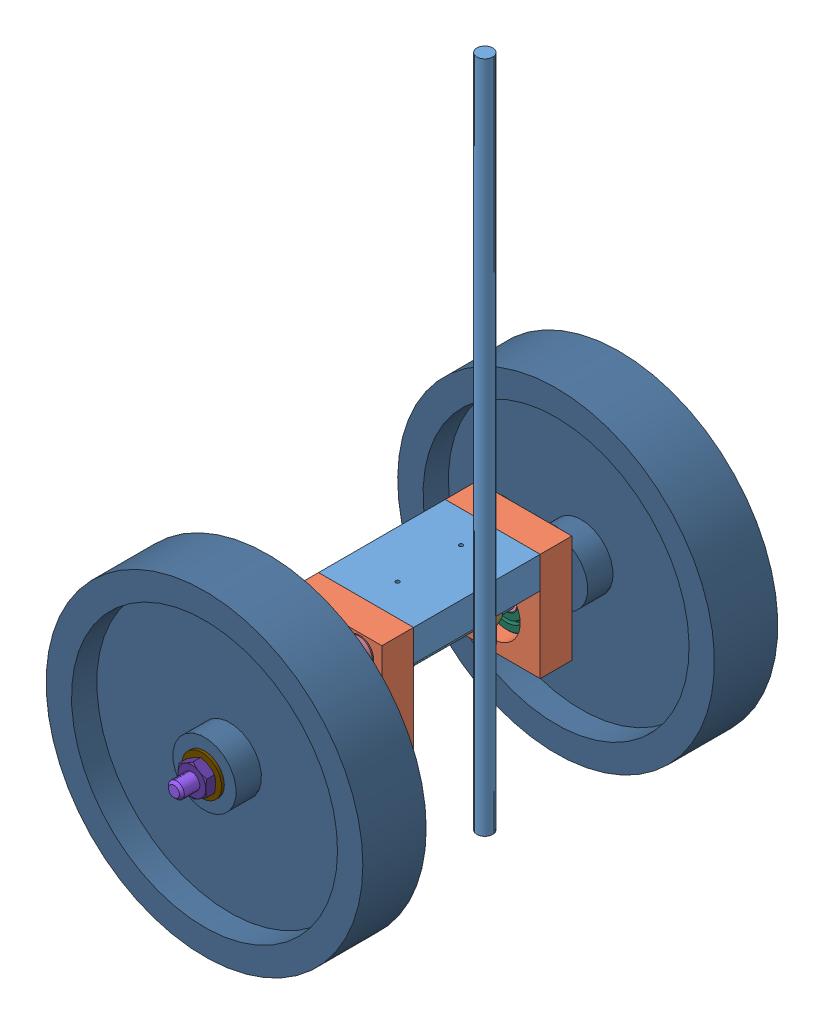
SolidWorks assembly Front Axle Assembly, configuration Default. Lengths in mm.
Overall size (164.58 298.79 190.98).
31 component instances, 20 part files, 65 mates.
Components (placement in the parent):
- Connection Front Suspention-1: Connection Front Suspention [Default] at (-53.6547 15.4423 62.2716) size (38.1 12.7 50.8)
- suspension front-1: suspension front [Default] at (-72.7047 -21.3877 74.9716) size (38.1 43.18 12.7)
- suspension front-2: suspension front [Default] at (-72.7047 -21.3877 11.4716) size (38.1 43.18 12.7)
- Slide Wing Nut-1: Slide Wing Nut [Default] at (-53.6547 8.2033 36.8716) x (0 0 1) z (0 -1 0) size (50.8 6.48 7.05)
- muffle bearing-1: muffle bearing [Default] at (-53.6547 -6.1477 -1.2284) size (8 8 7)
- muffle bearing-2: muffle bearing [Default] at (-53.6547 -6.1477 67.9716) size (8 8 7)
- Threaded Axle Front Left-1: Threaded Axle Front Left [Default] at (-53.6547 -6.1477 83.7836) x (0.967821 0.251639 0) z (0 0 1) size (6.35 6.35 135.47)
- Adapter One-Way-Bearing-1: Adapter One-Way-Bearing [Default] at (-53.6547 -6.1477 74.9716) x (-0.990269 0.139163 0) z (0 0 -1) size (45 45 20.32)
- Muffle One-Way-Bearing-1: Muffle One-Way-Bearing [Default] at (-53.6547 -6.1477 84.2916) size (15 15 11)
- Threaded Axle Front Right-1: Threaded Axle Front Right [Default] at (-53.6547 -6.1477 139.2916) x (0.848775 -0.528754 0) z (0 0 1) size (6.35 6.35 55)
- muffle wheel right-1: muffle wheel right [Default] at (-53.6547 -6.1477 95.2916) x (0.552032 0.833823 0) z (0 0 1) size (7.94 7.94 31.75)
- Wheel-1: Wheel [Default] at (-53.6547 -6.1477 114.3416) x (0.992874 0.119172 0) z (0 0 1) size (127 127 25.4)
- muffle wheel left-1: muffle wheel left [Default] at (-53.6547 -6.1477 -39.3284) size (7.94 7.94 38.1)
- Wheel-2: Wheel [Default] at (-53.6547 -6.1477 -26.6284) x (-0.36486 0.931062 0) z (0 0 1) size (127 127 25.4)
- Wingnut-1: Wingnut [Default] at (-63.224 -102.9399 -69.9379) x (0 -1 0) z (0 0 1) size (25.24 12.25 6.43)
- Button Head Hex Drive Screw 1-4-28-1: Button Head Hex Drive Screw 1-4-28 [Default] at (7.3275 5.2304 29.6861) size (11.1 11.1 16.71)
- Button Head Hex Drive Screw 1-4-28-2: Button Head Hex Drive Screw 1-4-28 [Default] at (-21.1014 44.8149 44.057) x (0.919454 0.393198 0) z (0 0 -1) size (11.1 11.1 16.71)
- Button Head Hex Drive Screw 1-4-28-3: Button Head Hex Drive Screw 1-4-28 [Default] at (-19.8729 61.5855 44.057) x (0.622111 0.782929 0) z (0 0 -1) size (11.1 11.1 16.71)
- Button Head Hex Drive Screw 1-4-28-4: Button Head Hex Drive Screw 1-4-28 [Default] at (-12.9925 5.2304 29.6861) size (11.1 11.1 16.71)
- Button Head Hex Drive Screw 1-64-1: Button Head Hex Drive Screw 1-64 [Default] at (-66.0699 34.9913 37.8914) x (-0.998887 0 -0.047164) z (0 -1 0) size (3.28 3.28 7.41)
- Button Head Hex Drive Screw 1-64-2: Button Head Hex Drive Screw 1-64 [Default] at (-37.2671 34.9913 19.4802) x (0.551582 0 -0.83412) z (0 -1 0) size (3.28 3.28 7.41)
- 608 Ball Bearing-1: 608 Ball Bearing [Default] at (-39.5024 -7.5493 -10.4793) size (22 22 7)
- 608 Ball Bearing-2: 608 Ball Bearing [Default] at (-39.5024 -7.5493 58.7207) size (22 22 7)
- One-Way-Bearing-1: One-Way-Bearing [Default] at (-39.7809 -11.9333 83.3481) x (0.996606 0.082318 0) z (0 0 1) size (35 35 11)
- Stainless Steel Thin Hex Nut 1-4-28-1: Stainless Steel Thin Hex Nut 1-4-28 [Default] at (-18.3908 36.8704 -65.2317) x (0.923728 0.383049 0) z (0.383049 -0.923728 0) size (11.11 4.67 12.83)
- Stainless Steel Thin Hex Nut 1-4-28-3: Stainless Steel Thin Hex Nut 1-4-28 [Default] at (-4.6024 -32.3769 152.9449) x (1 0 0) z (0 1 0) size (11.11 4.67 12.83)
- Stainless Steel Thin Hex Nut 1-4-28-4: Stainless Steel Thin Hex Nut 1-4-28 [Default] at (-4.6024 -32.3769 88.8139) x (1 0 0) z (0 1 0) size (11.11 4.67 12.83)
- 316 Stainless Steel Washer-1: 316 Stainless Steel Washer [Default] at (-18.7651 29.0423 -40.1203) x (1 0 0) z (0 -1 0) size (15.87 1.09 15.87)
- 316 Stainless Steel Washer-2: 316 Stainless Steel Washer [Default] at (-18.7651 -41.3376 127.8334) x (1 0 0) z (0 1 0) size (15.87 1.09 15.87)
- Wooden Rod-1: Wooden Rod [Default] at (-31.4297 -59.6477 36.8716) x (-0.156429 0 -0.987689) z (0 1 0) size (6.35 6.35 270)
- Compression Spring Break-1: Compression Spring Break [Default] at (-95.3507 -1.2922 45.8268) x (-0.627574 0.778557 0) z (0.778557 0.627574 0) size (7.88 17.75 8)
Mates (geometry in assembly coordinates):
- Coincident2: coincident: plane of Connection Front Suspention-1 through (-53.6547 15.4423 11.4716) normal (0 0 -1); plane of suspension front-2 through (-72.7047 -21.3877 11.4716) normal (0 0 1)
- Coincident3: coincident: plane of Connection Front Suspention-1 through (-72.7047 21.7923 11.4716) normal (0 1 0); plane of suspension front-2 through (-72.7047 21.7923 -1.2284) normal (0 1 0)
- Coincident4: coincident: plane of Connection Front Suspention-1 through (-72.7047 9.0923 11.4716) normal (-1 0 0); plane of suspension front-2 through (-72.7047 -21.3877 -1.2284) normal (-1 0 0)
- Coincident5: coincident: plane of Connection Front Suspention-1 through (-53.6547 15.4423 62.2716) normal (0 0 1); plane of suspension front-1 through (-72.7047 -21.3877 62.2716) normal (0 0 -1)
- Coincident6: coincident: plane of Connection Front Suspention-1 through (-72.7047 21.7923 11.4716) normal (0 1 0); plane of suspension front-1 through (-72.7047 21.7923 62.2716) normal (0 1 0)
- Coincident7: coincident: plane of Connection Front Suspention-1 through (-34.6047 9.0923 11.4716) normal (1 0 0); plane of suspension front-1 through (-34.6047 -21.3877 62.2716) normal (1 0 0)
- Coincident15: coincident: plane of Connection Front Suspention-1 through (-72.7047 9.0923 11.4716) normal (0 -1 0); plane of Slide Wing Nut-1 through (-53.6547 9.0923 36.8716) normal (0 1 0)
- Concentric7: concentric: circle of Connection Front Suspention-1; circle of Slide Wing Nut-1
- Coincident18: coincident: plane of suspension front-1 through (-72.7047 -21.3877 62.2716) normal (0 0 -1); plane of Slide Wing Nut-1 through (-50.4167 2.0444 62.2716) normal (0 0 1)
- Concentric14: concentric: cylinder of muffle bearing-2 through (-53.6547 -6.1477 74.9716) axis (0 0 -1) radius 2.555; cylinder of Threaded Axle Front Left-1 through (-53.6547 -6.1477 -51.6864) axis (0 0 1) radius 3.175
- Concentric15: concentric: cylinder of Threaded Axle Front Left-1 through (-53.6547 -6.1477 -51.6864) axis (0 0 1) radius 3.175; circle of Adapter One-Way-Bearing-1
- Concentric18: concentric: cylinder of Muffle One-Way-Bearing-1 through (-53.6547 -6.1477 95.2916) axis (0 0 -1) radius 2.555; cylinder of Threaded Axle Front Right-1 through (-53.6547 -6.1477 84.2916) axis (0 0 1) radius 3.175
- Coincident28: coincident: plane of Muffle One-Way-Bearing-1 through (-53.6547 -6.1477 84.2916) normal (0 0 -1); plane of Threaded Axle Front Right-1 through (-53.6547 -6.1477 84.2916) normal (0 0 -1)
- Concentric19: concentric: cylinder of Threaded Axle Front Right-1 through (-53.6547 -6.1477 84.2916) axis (0 0 1) radius 3.175; cylinder of muffle wheel right-1 through (-53.6547 -6.1477 127.0416) axis (0 0 -1) radius 2.555
- Coincident29: coincident: plane of Muffle One-Way-Bearing-1 through (-53.6547 -6.1477 95.2916) normal (0 0 1); plane of muffle wheel right-1 through (-53.6547 -6.1477 95.2916) normal (0 0 -1)
- Concentric20: concentric: cylinder of muffle wheel right-1 through (-53.6547 -6.1477 127.0416) axis (0 0 -1) radius 3.9688; cylinder of Wheel-1 through (-53.6547 -6.1477 101.6416) axis (0 0 1) radius 3.9688
- Coincident30: coincident: plane of muffle wheel right-1 through (-53.6547 -6.1477 127.0416) normal (0 0 1); plane of Wheel-1 through (-53.6547 -6.1477 127.0416) normal (0 0 1)
- Concentric22: concentric: cylinder of Threaded Axle Front Left-1 through (-53.6547 -6.1477 -51.6864) axis (0 0 1) radius 3.175; cylinder of muffle wheel left-1 through (-53.6547 -6.1477 -1.2284) axis (0 0 -1) radius 2.555
- Concentric23: concentric: cylinder of muffle wheel left-1 through (-53.6547 -6.1477 -1.2284) axis (0 0 -1) radius 3.9688; cylinder of Wheel-2 through (-53.6547 -6.1477 -39.3284) axis (0 0 1) radius 3.9688
- Coincident33: coincident: plane of muffle wheel left-1 through (-53.6547 -6.1477 -39.3284) normal (0 0 -1); plane of Wheel-2 through (-53.6547 -6.1477 -39.3284) normal (0 0 -1)
- Concentric30: concentric: cylinder of Threaded Axle Front Left-1 through (-53.6547 -6.1477 -51.6864) axis (0 0 1) radius 3.175; circle of Wingnut-1
- Parallel1: parallel: plane of Slide Wing Nut-1 through (-56.0037 10.9344 36.8716) normal (1 0 0); plane of Wingnut-1 through (-55.1926 0.0039 11.2001) normal (-1 0 0)
- Distance2: distance = 0.1 mm: plane of Wingnut-1 through (-53.6547 -6.1477 11.5716) normal (0 0 -1); plane of suspension front-2 through (-72.7047 -21.3877 11.4716) normal (0 0 1)
- Concentric35: concentric: circle of Connection Front Suspention-1; circle of Button Head Hex Drive Screw 1-64-2
- Coincident54: coincident: plane of Slide Wing Nut-1 through (-53.6547 8.2033 36.8716) normal (0 -1 0); plane of Button Head Hex Drive Screw 1-64-2 through (-52.2882 8.2033 25.0752) normal (0 1 0)
- Concentric36: concentric: circle of Connection Front Suspention-1; circle of Button Head Hex Drive Screw 1-64-1
- Coincident55: coincident: plane of Slide Wing Nut-1 through (-53.6547 8.2033 36.8716) normal (0 -1 0); plane of Button Head Hex Drive Screw 1-64-1 through (-53.5774 8.2033 47.9351) normal (0 1 0)
- Concentric37: concentric: cylinder of 608 Ball Bearing-2 through (-53.6547 -6.1477 74.9716) axis (0 0 1) radius 11; cylinder of suspension front-1 through (-53.6547 -6.1477 62.2716) axis (0 0 1) radius 11
- Coincident56: coincident: plane of 608 Ball Bearing-2 through (-53.6547 4.5023 74.9716) normal (0 0 1); plane of suspension front-1 through (-72.7047 -21.3877 74.9716) normal (0 0 1)
- Concentric38: concentric: cylinder of suspension front-2 through (-53.6547 -6.1477 -1.2284) axis (0 0 1) radius 11; cylinder of 608 Ball Bearing-1 through (-53.6547 -6.1477 5.7716) axis (0 0 1) radius 11
- Coincident57: coincident: plane of suspension front-2 through (-72.7047 -21.3877 -1.2284) normal (0 0 -1); plane of 608 Ball Bearing-1 through (-53.6547 4.5023 -1.2284) normal (0 0 -1)
- Concentric39: concentric: cylinder of muffle bearing-1 through (-53.6547 -6.1477 5.7716) axis (0 0 -1) radius 4; cylinder of 608 Ball Bearing-1 through (-53.6547 -6.1477 5.7716) axis (0 0 1) radius 4
- Coincident58: coincident: plane of muffle bearing-1 through (-53.6547 -6.1477 -1.2284) normal (0 0 -1); plane of 608 Ball Bearing-1 through (-53.6547 -1.7977 -1.2284) normal (0 0 -1)
- Concentric40: concentric: cylinder of muffle bearing-2 through (-53.6547 -6.1477 74.9716) axis (0 0 -1) radius 4; cylinder of 608 Ball Bearing-2 through (-53.6547 -6.1477 74.9716) axis (0 0 1) radius 4
- Coincident59: coincident: plane of muffle bearing-2 through (-53.6547 -6.1477 74.9716) normal (0 0 1); plane of 608 Ball Bearing-2 through (-53.6547 0.693 74.9716) normal (0 0 1)
- Coincident60: coincident: plane of muffle wheel left-1 through (-53.6547 -6.1477 -1.2284) normal (0 0 1); plane of 608 Ball Bearing-1 through (-53.6547 4.5023 -1.2284) normal (0 0 -1)
- Coincident61: coincident: plane of Adapter One-Way-Bearing-1 through (-53.6547 -6.1477 74.9716) normal (0 0 -1); plane of 608 Ball Bearing-2 through (-53.6547 0.693 74.9716) normal (0 0 1)
- Concentric41: concentric: cylinder of Adapter One-Way-Bearing-1 through (-53.6547 -6.1477 84.2916) axis (0 0 1) radius 17.5; cylinder of One-Way-Bearing-1 through (-53.6547 -6.1477 95.2916) axis (0 0 1) radius 17.5
- Coincident62: coincident: plane of Adapter One-Way-Bearing-1 through (-53.6547 -6.1477 95.2916) normal (0 0 1); plane of One-Way-Bearing-1 through (-55.05 10.7448 95.2916) normal (0 0 1)
- Concentric43: concentric: cylinder of Muffle One-Way-Bearing-1 through (-53.6547 -6.1477 95.2916) axis (0 0 -1) radius 7.5; cylinder of One-Way-Bearing-1 through (-53.6547 -6.1477 95.2916) axis (0 0 1) radius 7.5
- Coincident63: coincident: plane of Muffle One-Way-Bearing-1 through (-53.6547 -6.1477 95.2916) normal (0 0 1); plane of One-Way-Bearing-1 through (-55.05 10.7448 95.2916) normal (0 0 1)
- Coincident64: coincident: plane of Wheel-2 through (-53.6547 -6.1477 -39.3284) normal (0 0 -1); plane of 316 Stainless Steel Washer-1 through (-53.6547 -6.1477 -39.3284) normal (0 0 1)
- Concentric44: concentric: circle of Threaded Axle Front Left-1; circle of 316 Stainless Steel Washer-1
- Coincident65: coincident: plane of Wheel-1 through (-53.6547 -6.1477 127.0416) normal (0 0 1); plane of 316 Stainless Steel Washer-2 through (-53.6547 -6.1477 127.0416) normal (0 0 -1)
- Concentric45: concentric: circle of Threaded Axle Front Right-1; circle of 316 Stainless Steel Washer-2
- Concentric46: concentric: circle of Threaded Axle Front Right-1; circle of Stainless Steel Thin Hex Nut 1-4-28-3
- Coincident67: coincident: plane of Stainless Steel Thin Hex Nut 1-4-28-3 through (-59.211 -9.3556 128.1338) normal (0 0 -1); plane of 316 Stainless Steel Washer-2 through (-53.6547 -6.1477 128.1338) normal (0 0 1)
- Coincident68: coincident: plane of Stainless Steel Thin Hex Nut 1-4-28-1 through (-60.016 -5.3128 -40.4206) normal (0 0 1); plane of 316 Stainless Steel Washer-1 through (-53.6547 -6.1477 -40.4206) normal (0 0 -1)
- Concentric47: concentric: circle of Threaded Axle Front Left-1; circle of Stainless Steel Thin Hex Nut 1-4-28-1
- Coincident69: coincident: cylinder of Threaded Axle Front Left-1 through (-53.6547 -6.1477 -51.6864) axis (0 0 1) radius 3.175; circle of Stainless Steel Thin Hex Nut 1-4-28-4
- Coincident71: coincident: plane of 608 Ball Bearing-2 through (-53.6547 -1.7977 67.9716) normal (0 0 -1); plane of Stainless Steel Thin Hex Nut 1-4-28-4 through (-59.211 -9.3556 67.9716) normal (0 0 1)
- Parallel2: parallel: plane of Connection Front Suspention-1 through (-72.7047 21.7923 11.4716) normal (0 1 0); plane of Wooden Rod-1 through (-31.4297 -59.6477 36.8716) normal (0 -1 0)
- Tangent1: tangent: plane of Connection Front Suspention-1 through (-34.6047 9.0923 11.4716) normal (1 0 0); cylinder of Wooden Rod-1 through (-31.4297 210.3523 36.8716) axis (0 -1 0) radius 3.175
- Distance4: distance = 38.26 mm: plane of Wooden Rod-1 through (-31.4297 -59.6477 36.8716) normal (0 -1 0); plane of suspension front-1 through (-72.7047 -21.3877 62.2716) normal (0 -1 0)
- Distance5: distance = 38.1 mm: cylinder of Wooden Rod-1 through (-31.4297 210.3523 36.8716) axis (0 -1 0) radius 3.175; plane of suspension front-1 through (-72.7047 -21.3877 74.9716) normal (0 0 1)
- Coincident73: coincident: plane of Stainless Steel Thin Hex Nut 1-4-28-4 through (-59.211 -9.3556 64.0028) normal (0 0 -1); plane of Compression Spring Break-1 through (-54.2668 -11.6211 64.0028) normal (0 0 1)
- Lock1: lock: unknown of Threaded Axle Front Left-1; unknown of Compression Spring Break-1
- Concentric48: concentric: circle of suspension front-2; circle of Button Head Hex Drive Screw 1-4-28-2
- Coincident74: coincident: plane of suspension front-2 through (-72.7047 -21.3877 -1.2284) normal (0 0 -1); plane of Button Head Hex Drive Screw 1-4-28-2 through (-61.6325 10.3394 -1.2284) normal (0 0 1)
- Concentric49: concentric: circle of suspension front-2; circle of Button Head Hex Drive Screw 1-4-28-3
- Coincident75: coincident: plane of suspension front-2 through (-72.7047 -21.3877 -1.2284) normal (0 0 -1); plane of Button Head Hex Drive Screw 1-4-28-3 through (-39.1495 11.9897 -1.2284) normal (0 0 1)
- Concentric50: concentric: circle of suspension front-1; circle of Button Head Hex Drive Screw 1-4-28-1
- Coincident76: coincident: plane of suspension front-1 through (-72.7047 -21.3877 74.9716) normal (0 0 1); plane of Button Head Hex Drive Screw 1-4-28-1 through (-43.4947 20.9922 74.9716) normal (0 0 -1)
- Concentric51: concentric: circle of suspension front-1; circle of Button Head Hex Drive Screw 1-4-28-4
- Coincident77: coincident: plane of suspension front-1 through (-72.7047 -21.3877 74.9716) normal (0 0 1); plane of Button Head Hex Drive Screw 1-4-28-4 through (-63.8147 20.9922 74.9716) normal (0 0 -1)
